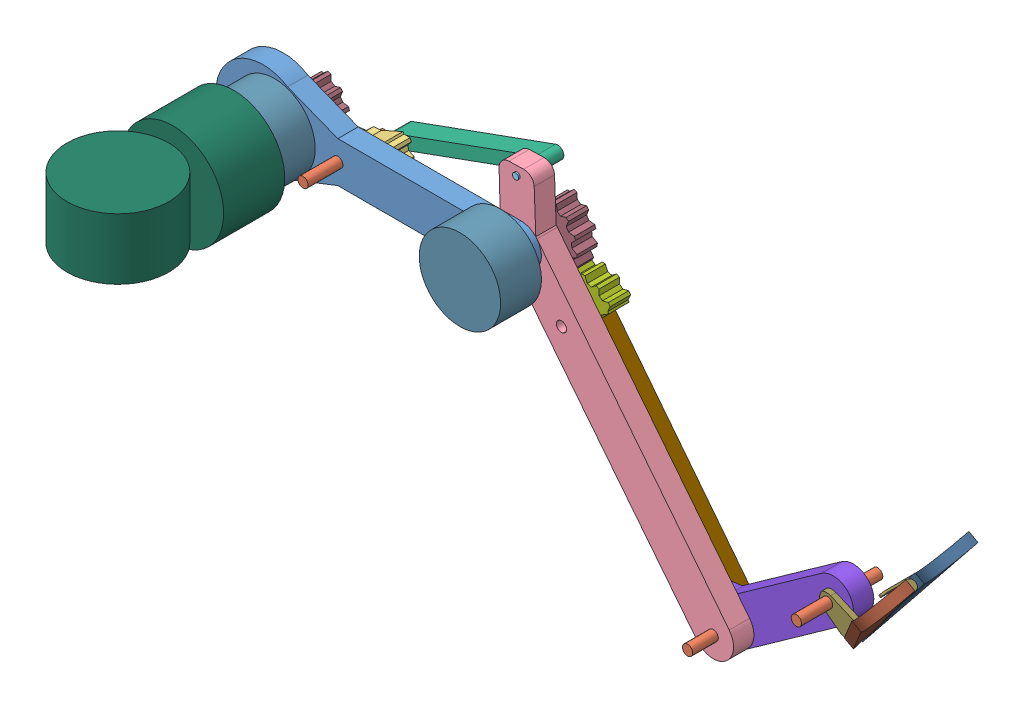
SolidWorks assembly Assemblage_leg_gauche, configuration Défaut. Lengths in mm.
Overall size (330.15 177.82 150.42).
22 component instances, 15 part files, 32 mates.
Components (placement in the parent):
- femur-1: femur [Défaut] at (-36.3804 -7.677 100) size (149.91 46.21 10)
- grand axe-1: grand axe [Défaut] at (-36.3804 2.323 87.1079) x (-0.546581 0.837406 0) z (0 0 1) size (5 5 40)
- PIGNON1-2: PIGNON1 [Défaut] at (-36.3804 2.323 100) x (0.729439 0.684046 0) z (0 0 -1) size (34.33 27.43 20)
- tibia-1: tibia [Défaut] at (35.7831 -3.889 90) x (0.6212 -0.783652 0) z (0 0 1) size (192.09 33.32 10)
- petit axe-3: petit axe [Défaut] at (41.6437 30.6294 80.7241) x (0.626532 0.779396 0) z (0 0 1) size (3 3 20)
- segment_L3-1: segment_L3 [Défaut] at (-29.8831 7.8715 90) x (0.940049 0.34104 0) z (0 0 -1) size (81 6 10)
- PIGNON2-1: PIGNON2 [Défaut] at (63.498 -22.7538 90) x (-0.348796 -0.937199 0) z (0 0 -1) size (34.33 27.43 20)
- grand axe-4: grand axe [Défaut] at (138.0421 -116.792 72.6028) x (0.258928 -0.965897 0) z (0 0 1) size (5 5 40)
- tarto-1: tarto [Défaut] at (143.8389 -124.9404 80) x (0.814839 0.579687 0) z (0 0 1) size (91.56 26.49 10)
- petit axe-4: petit axe [Défaut] at (123.563 -118.5908 69.3199) x (0.999981 -0.006182 0) z (0 0 1) size (3 3 20)
- segment_L3 - Copie-1: segment_L3 - Copie [Défaut] at (53.4258 -33.7982 70) x (0.61613 -0.787645 0) z (0 0 1) size (116 6 10)
- grand axe-5: grand axe [Défaut] at (186.9324 -82.0108 68.0818) x (0.988863 0.148825 0) z (0 0 1) size (5 5 40)
- palme_last_v-2: palme_last_v [Défaut] at (255.3784 -102.2609 75.7772) x (-0.08399 0.063631 -0.994433) z (-0.792647 0.600506 0.105372) size (63.15 52.21 24.3)
  - part1_palme-1: part1_palme [Défaut] at (-7.6046 -22.9375 50) size (34.09 50 5)
  - part2_palme-1: part2_palme [Défaut] at (-12.5766 -22.9375 54.9823) x (-1 0 0) z (0 0 -1) size (34.09 50 5)
  - arret_rotation-1: arret_rotation [Défaut] at (-10.0906 -19.7229 52.4912) x (0.105372 0 0.994433) z (0 1 0) size (22.5 18.23 49)
- PIGNON_moteur-2: PIGNON_moteur [Défaut] at (-67.4715 2.323 90) x (-0.805056 -0.593199 0) z (0 0 1) size (34.33 27.43 20)
- PIGNON_moteur-3: PIGNON_moteur [Défaut] at (43.6196 2.323 80) x (-0.795669 -0.605732 0) z (0 0 1) size (34.33 27.43 20)
- moteur-1: moteur [Défaut] at (-67.4715 2.323 130) x (0.956017 0.293311 0) z (0 0 -1) size (40 40 30)
- moteur-2: moteur [Défaut] at (43.6196 2.323 130) x (0.587119 0.809501 0) z (0 0 -1) size (40 40 30)
- moteur_hanche-1: moteur_hanche [Défaut] at (-67.4715 2.323 160) x (0.999949 0.010063 0) z (0 0 -1) size (50 50 30)
- moteur_hanche-2: moteur_hanche [Défaut] at (-69.428 18.9606 185) x (1 0 0) z (0 -1 0) size (50 50 30)
Mates (geometry in assembly coordinates):
- Coaxiale1: concentric aligned: cylinder of femur-1 through (-36.3804 2.323 110) axis (0 0 -1) radius 2.5; cylinder of grand axe-1 through (-36.3804 2.323 127.1079) axis (0 0 -1) radius 2.5
- Coaxiale6: concentric aligned: cylinder of grand axe-1 through (-36.3804 2.323 127.1079) axis (0 0 -1) radius 2.5; cylinder of PIGNON1-2 through (-36.3804 2.323 100) axis (0 0 -1) radius 2.5
- Coaxiale11: concentric aligned: cylinder of PIGNON1-2 through (-28.86 5.0514 80) axis (0 0 1) radius 1.5; cylinder of segment_L3-1 through (-28.86 5.0514 80) axis (0 0 1) radius 1.5
- Coaxiale12: concentric anti-aligned: cylinder of petit axe-3 through (41.6437 30.6294 100.7241) axis (0 0 -1) radius 1.5; cylinder of segment_L3-1 through (41.6437 30.6294 80) axis (0 0 1) radius 1.5
- Coaxiale15: concentric aligned: cylinder of grand axe-4 through (138.0421 -116.792 112.6028) axis (0 0 -1) radius 2.5; cylinder of tarto-1 through (138.0421 -116.792 90) axis (0 0 -1) radius 2.5
- Coaxiale16: concentric aligned: cylinder of tarto-1 through (123.563 -118.5908 90) axis (0 0 -1) radius 1.5; cylinder of petit axe-4 through (123.563 -118.5908 89.3199) axis (0 0 -1) radius 1.5
- Coaxiale17: concentric anti-aligned: cylinder of petit axe-4 through (123.563 -118.5908 89.3199) axis (0 0 -1) radius 1.5; circle of segment_L3 - Copie-1
- Coaxiale18: concentric anti-aligned: cylinder of PIGNON2-1 through (55.7887 -31.9499 70) axis (0 0 1) radius 1.5; cylinder of segment_L3 - Copie-1 through (55.7887 -31.9499 80) axis (0 0 -1) radius 1.5
- Coaxiale20: concentric aligned: cylinder of tarto-1 through (186.9324 -82.0108 90) axis (0 0 -1) radius 2.5; cylinder of grand axe-5 through (186.9324 -82.0108 108.0818) axis (0 0 -1) radius 2.5
- Coaxiale21: concentric aligned: cylinder of grand axe-5 through (186.9324 -82.0108 108.0818) axis (0 0 -1) radius 2.5; cylinder of palme_last_v-2/arret_rotation-1 through (186.9324 -82.0108 100) axis (0 0 -1) radius 2.5
- Coaxiale24: concentric aligned: cylinder of femur-1 through (-67.4715 2.323 110) axis (0 0 -1) radius 2.5; cylinder of PIGNON_moteur-2 through (-67.4715 2.323 110) axis (0 0 -1) radius 2.5
- Coaxiale26: concentric aligned: cylinder of tibia-1 through (138.0421 -116.792 100) axis (0 0 -1) radius 2.5; cylinder of grand axe-4 through (138.0421 -116.792 112.6028) axis (0 0 -1) radius 2.5
- Coaxiale27: concentric aligned: cylinder of tibia-1 through (41.6437 30.6294 100) axis (0 0 -1) radius 1.5; cylinder of petit axe-3 through (41.6437 30.6294 100.7241) axis (0 0 -1) radius 1.5
- Coaxiale28: concentric aligned: cylinder of tibia-1 through (43.6196 2.323 100) axis (0 0 -1) radius 2.5; cylinder of PIGNON_moteur-3 through (43.6196 2.323 100) axis (0 0 -1) radius 2.5
- Coaxiale29: concentric anti-aligned: cylinder of femur-1 through (-67.4715 2.323 110) axis (0 0 -1) radius 2.5; cylinder of moteur-1 through (-67.4715 2.323 100) axis (0 0 1) radius 2.5
- Coaxiale30: concentric aligned: cylinder of femur-1 through (43.6196 2.323 110) axis (0 0 -1) radius 2.5; cylinder of PIGNON_moteur-3 through (43.6196 2.323 100) axis (0 0 -1) radius 2.5
- Coaxiale31: concentric anti-aligned: cylinder of femur-1 through (43.6196 2.323 110) axis (0 0 -1) radius 2.5; cylinder of moteur-2 through (43.6196 2.323 100) axis (0 0 1) radius 2.5
- Coaxiale32: concentric aligned: cylinder of moteur-1 through (-67.4715 2.323 110) axis (0 0 1) radius 20; cylinder of moteur_hanche-1 through (-67.4715 2.323 130) axis (0 0 1) radius 25
- Coïncidente1: coincident anti-aligned: plane of moteur-1 through (-67.4715 2.323 130) normal (0 0 1); plane of moteur_hanche-1 through (-67.4715 2.323 130) normal (0 0 -1)
- Coïncidente3: coincident anti-aligned: plane of femur-1 through (-73.1882 2.323 100) normal (0 0 -1); plane of PIGNON_moteur-2 through (-67.4715 2.323 100) normal (0 0 1)
- Coïncidente4: coincident anti-aligned: plane of femur-1 through (-73.1882 2.323 110) normal (0 0 1); plane of moteur-1 through (-67.4715 2.323 110) normal (0 0 -1)
- Coïncidente5: coincident anti-aligned: plane of femur-1 through (-73.1882 2.323 100) normal (0 0 -1); plane of PIGNON1-2 through (-36.3804 2.323 100) normal (0 0 1)
- Coïncidente6: coincident anti-aligned: plane of PIGNON1-2 through (-36.3804 2.323 90) normal (0 0 -1); plane of segment_L3-1 through (-28.86 5.0514 90) normal (0 0 1)
- Coïncidente8: coincident anti-aligned: plane of femur-1 through (-73.1882 2.323 110) normal (0 0 1); plane of moteur-2 through (43.6196 2.323 110) normal (0 0 -1)
- Coïncidente10: coincident anti-aligned: plane of femur-1 through (-73.1882 2.323 100) normal (0 0 -1); plane of tibia-1
- Coïncidente12: coincident anti-aligned: plane of tibia-1; plane of PIGNON_moteur-3 through (43.6196 2.323 90) normal (0 0 1)
- Coïncidente13: coincident anti-aligned: plane of tibia-1; plane of tarto-1 through (186.9324 -82.0108 90) normal (0 0 1)
- Coïncidente15: coincident anti-aligned: plane of tibia-1; plane of PIGNON2-1 through (63.498 -22.7538 90) normal (0 0 1)
- Coïncidente18: coincident anti-aligned: plane of PIGNON2-1 through (63.498 -22.7538 80) normal (0 0 -1); plane of segment_L3 - Copie-1 through (55.7887 -31.9499 80) normal (0 0 1)
- Coïncidente19: coincident anti-aligned: plane of tarto-1 through (186.9324 -82.0108 90) normal (0 0 1); plane of palme_last_v-2/arret_rotation-1 through (196.9394 -94.7181 90) normal (0 0 -1)
- Coaxiale33: concentric aligned: cylinder of tibia-1 through (63.498 -22.7538 100) axis (0 0 -1) radius 2.5; cylinder of PIGNON2-1 through (63.498 -22.7538 90) axis (0 0 -1) radius 2.5
- Tangent1: tangent anti-aligned: plane of moteur_hanche-1 through (-67.4715 2.323 160) normal (0 0 1); cylinder of moteur_hanche-2 through (-69.428 -11.0394 185) axis (0 1 0) radius 25
